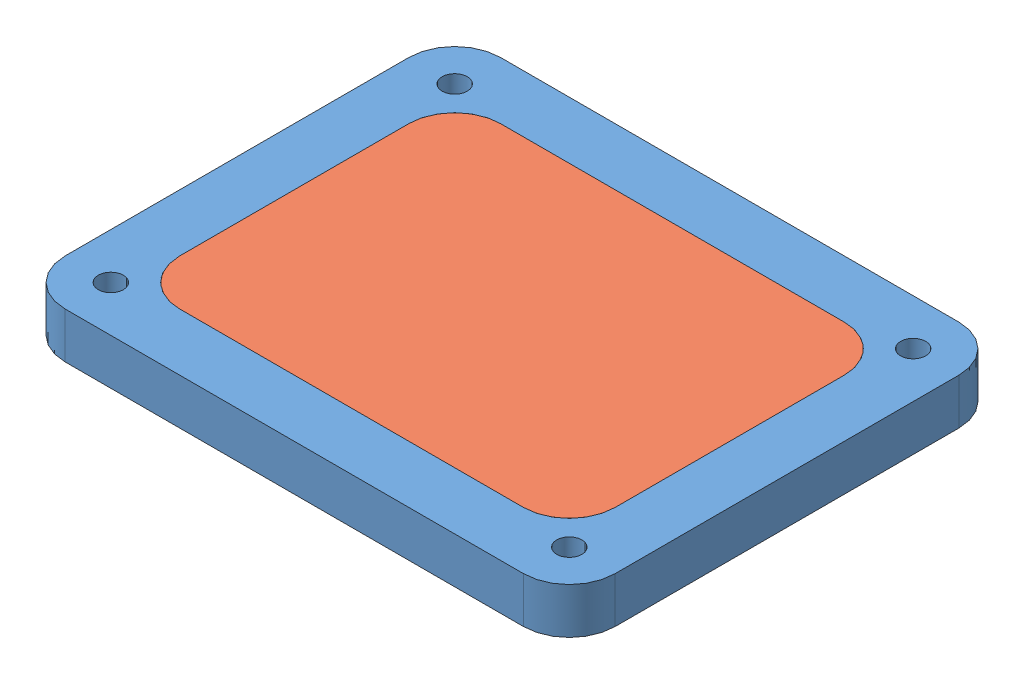
SolidWorks assembly glasswindow_cover, configuration Default. Lengths in mm.
Overall size (120 10 95).
2 component instances, 2 part files, 3 mates.
Components (placement in the parent):
- glasscover-1: glasscover [Default] at (4.3361 -5.8911 -1.6827) size (120 10 95)
- Glasswindow-1: Glasswindow [Default] at (4.3361 1.1089 -1.6827) size (95 3 70)
Mates (geometry in assembly coordinates):
- Coincident1: coincident anti-aligned: plane of glasscover-1 through (51.8361 1.1089 33.3173) normal (0 0 -1); plane of Glasswindow-1 through (41.8361 4.1089 33.3173) normal (0 0 1)
- Coincident2: coincident anti-aligned: plane of glasscover-1 through (-43.1639 1.1089 -36.6827) normal (0 1 0); plane of Glasswindow-1 through (41.8361 1.1089 -26.6827) normal (0 -1 0)
- Coincident3: coincident anti-aligned: plane of glasscover-1 through (-43.1639 1.1089 33.3173) normal (1 0 0); plane of Glasswindow-1 through (-43.1639 4.1089 23.3173) normal (-1 0 0)
